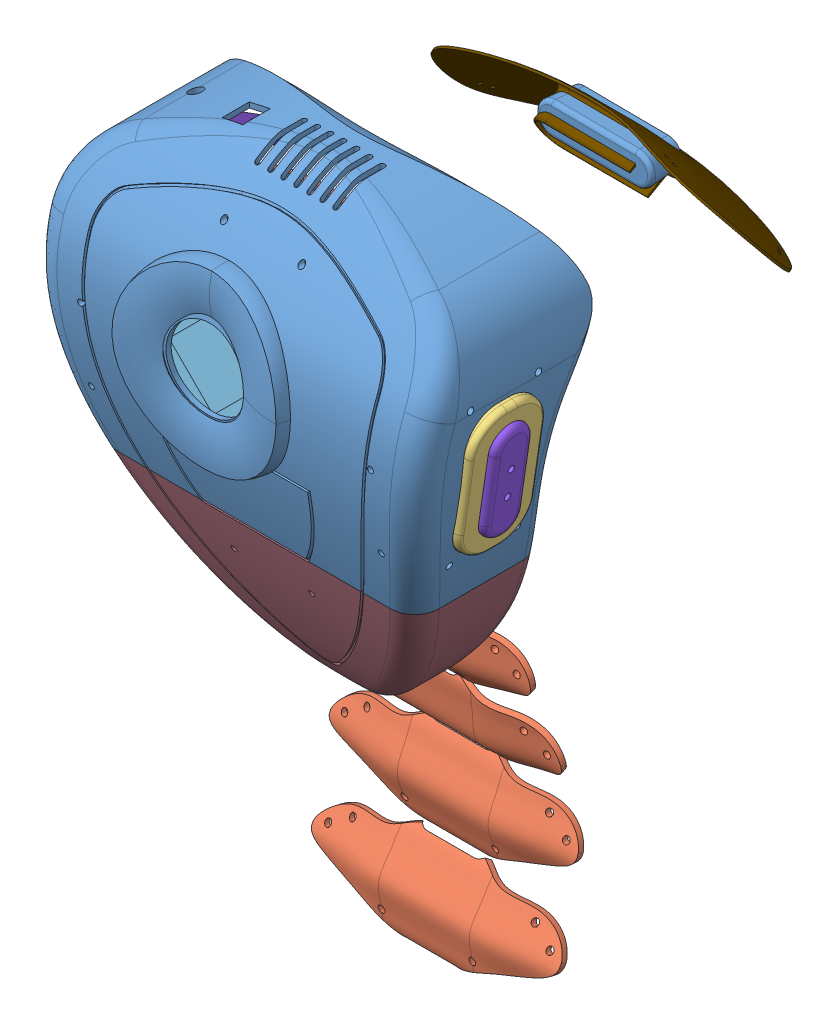
SolidWorks assembly Ensamble Mochila Render, configuration Default. Lengths in mm.
Overall size (331.65 592.36 403.8).
29 component instances, 21 part files, 47 mates.
Components (placement in the parent):
- backpack 2g bottom-1: backpack 2g bottom [Default] at (119.4145 250.7971 218.3899) size (331.65 355.76 156.42)
- Vertebra-1: Vertebra [Default] at (118.8196 71.875 196.4276) x (1 0 0) z (0 -0.948324 -0.317305) size (198 22.76 69.24)
- Part2-1: Part2 [Default] at (-30.5346 255.3553 293.3899) x (0.14708 -0.989125 0) z (0 0 1) size (104.05 10.05 58.05)
- Part2-2: Part2 [Default] at (269.3635 255.3553 293.3899) x (0.147081 0.989124 0) z (0 0 1) size (104.05 10.05 58.05)
- Jetson H-1: Jetson H [Default] at (-25.9313 294.8879 198.9465) x (0.707107 0.707107 0) z (0.707107 -0.707107 0) size (180 45.5 180)
  - Base-1: Base [Default] at (67.0689 90.6709 139.4266) size (180 3 180)
  - Board-1: Board [Default] at (67.0689 104.6709 139.4266) size (170 31.5 170)
  - Separador-1: Separador [Default] at (-7.9311 93.6709 214.4266) x (0.99477 0 -0.102141) z (0.102141 0 0.99477) size (6 11 6)
  - Separador-2: Separador [Default] at (142.0689 93.6709 64.4266) size (6 11 6)
  - Separador-3: Separador [Default] at (142.0689 93.6709 214.4266) size (6 11 6)
  - Separador-4: Separador [Default] at (-7.9311 93.6709 64.4266) size (6 11 6)
- Vertebra-2: Vertebra [Default] at (118.376 8.3161 174.5883) x (1 0 0) z (0 -0.913545 -0.406737) size (198 22.76 69.24)
- Vertebra-3: Vertebra [Default] at (118.6698 -138.0838 164.6524) x (1 0 0) z (0 -0.97237 0.233445) size (198 22.76 69.24)
- Vertebra-4: Vertebra [Default] at (118.6834 -66.4172 153.1876) x (1 0 0) z (0 -0.998135 0.061049) size (198 22.76 69.24)
- Pieza soporte bocina izquierda-1: Pieza soporte bocina izquierda [Default] at (249.7444 259.3959 292.8923) x (0.989124 -0.147081 0) z (0 0 1) size (30.45 130 93.17)
- Seguro bocina izquierda-1: Seguro bocina izquierda [Default] at (260.7409 231.3626 293.3899) x (0 0 -1) z (-0.147081 -0.989124 0) size (30 10.46 80)
- jetson holder ---1: jetson holder -- [Default] at (120.0816 243.7182 283.6173) x (-0.707107 0.707107 0) z (0.707107 0.707107 0) size (66.79 36.44 66.79)
- jetson holder ++-1: jetson holder ++ [Default] at (120.0846 243.7282 283.6173) x (0.707107 -0.707107 0) z (-0.707107 -0.707107 0) size (66.79 46.69 66.79)
- jetson holder -+-1: jetson holder -+ [Default] at (120.0781 243.7248 283.6173) x (0.707107 0.707107 0) z (0.707107 -0.707107 0) size (66.79 69.99 66.79)
- jetson holder +--1: jetson holder +- [Default] at (120.0881 243.7217 283.6173) x (-0.707107 -0.707107 0) z (-0.707107 0.707107 0) size (49.73 64.72 58.31)
- backpack 2g-2: backpack 2g [Default] at (119.4145 250.7971 218.3899) size (250.08 344.21 137.51)
- Pieza soporte bocina derecha-1: Pieza soporte bocina derecha [Default] at (8.867 262.3374 292.8923) x (0.989125 0.14708 0) z (0 0 1) size (17.29 130.75 82.59)
- Seguro bocina der-1: Seguro bocina der [Default] at (-68.831 274.9356 293.3899) x (0 0 1) z (-0.14708 0.989125 0) size (30 10.46 80)
- Union left-1: Union left [Default] at (232.1995 167.8342 278.3854) x (0.008119 -0.003198 -0.999962) z (0.930382 -0.366487 0.008727) size (60 40 6.53)
- Sensores-1: Sensores [Default] at (34.9607 359.3668 269.7709) x (-0.936644 -0.350185 -0.008276) z (0.006782 0.005492 -0.999962) size (110 12.3 30)
- Pecho-1: Pecho [Default] at (116.361 294.6343 51.4593) x (-0.999962 -0.006171 -0.006171) z (0.008727 -0.70708 -0.70708) size (284.4 58.67 170.86)
- Realsense-1: Realsense [Default] at (117.2497 289.9091 71.9103) x (-0.999962 0 -0.008727) z (0.008727 0 -0.999962) size (89.45 24.73 25)
- Broche-1: Broche [Default] at (120.0846 243.7282 283.6173) x (0.965926 -0.258819 0) z (0.258819 0.965926 0) size (250 4 250)
- Galss-1: Galss [Default] at (84.9691 289.9091 46.6277) x (0.999962 0 0.008727) z (-0.008727 0 0.999962) size (82.62 17.62 0.5)
Mates (geometry in assembly coordinates):
- Coincident1: coincident: point of backpack 2g bottom-1; point of Part2-2
- Coincident2: coincident: curve of backpack 2g bottom-1; unknown of Part2-2
- Coincident3: coincident anti-aligned: plane of backpack 2g bottom-1 through (-50.2025 228.7971 264.3899) normal (0 0 1); plane of Part2-2 through (263.4435 283.5325 264.3899) normal (0 0 -1)
- Coincident4: coincident: point of backpack 2g bottom-1; point of Part2-1
- Coincident5: coincident: edge_curve of backpack 2g bottom-1; unknown of Part2-1
- Coincident6: coincident anti-aligned: plane of backpack 2g bottom-1 through (-50.2025 228.7971 264.3899) normal (0 0 1); plane of Part2-1 through (-16.6722 230.1198 264.3899) normal (0 0 -1)
- Concentric1: concentric aligned: cylinder of backpack 2g bottom-1 through (331.3037 303.8839 266.8923) axis (-0.989124 0.147081 0) radius 2.5; cylinder of Pieza soporte bocina izquierda-1 through (272.8178 312.5806 266.8923) axis (-0.989124 0.147081 0) radius 2.5
- Concentric2: concentric aligned: cylinder of backpack 2g bottom-1 through (331.3037 303.8839 318.8923) axis (-0.989124 0.147081 0) radius 2.5; cylinder of Pieza soporte bocina izquierda-1 through (272.8178 312.5806 318.8923) axis (-0.989124 0.147081 0) radius 2.5
- Coincident7: coincident anti-aligned: plane of Part2-2 through (255.5011 230.1198 289.3899) normal (-0.989124 0.147081 0); plane of Pieza soporte bocina izquierda-1 through (255.5011 230.1198 289.3899) normal (0.989124 -0.147081 0)
- Concentric3: concentric aligned: cylinder of Pieza soporte bocina izquierda-1 through (245.6146 268.9967 293.3899) axis (0.989124 -0.147081 0) radius 2.5; cylinder of Seguro bocina izquierda-1 through (265.4344 266.0495 293.3899) axis (0.989124 -0.147081 0) radius 2.5
- Concentric4: concentric aligned: cylinder of Pieza soporte bocina izquierda-1 through (242.673 249.2142 293.3899) axis (0.989124 -0.147081 0) radius 2.5; cylinder of Seguro bocina izquierda-1 through (262.4928 246.267 293.3899) axis (0.989124 -0.147081 0) radius 2.5
- Coincident8: coincident anti-aligned: plane of Pieza soporte bocina izquierda-1 through (264.5813 257.1896 292.8923) normal (0.989124 -0.147081 0); plane of Seguro bocina izquierda-1 through (260.7409 231.3626 293.3899) normal (-0.989124 0.147081 0)
- Concentric5: concentric anti-aligned: cylinder of Jetson H-1/Base-1 through (110.0816 132.6368 292.6173) axis (0 0 -1) radius 2.5; cylinder of jetson holder ---1 through (110.0816 132.6368 283.6163) axis (0 0 1) radius 2.5
- Parallel1: parallel anti-aligned: cylinder of Jetson H-1/Base-1 through (130.0816 132.6368 292.6173) axis (0 0 -1) radius 2.5; cylinder of jetson holder ---1 through (130.0816 132.6368 283.6163) axis (0 0 1) radius 2.5
- Coincident9: coincident anti-aligned: plane of Jetson H-1/Base-1 through (120.0831 243.7232 289.6173) normal (0 0 -1); plane of jetson holder ---1 through (120.0816 243.7182 289.6173) normal (0 0 1)
- Coincident10: coincident aligned: circle of Jetson H-1/Base-1; cylinder of jetson holder ++-1 through (130.0846 354.8097 283.6163) axis (0 0 1) radius 2.5
- Parallel2: parallel anti-aligned: cylinder of Jetson H-1/Base-1 through (110.0846 354.8097 292.6173) axis (0 0 -1) radius 2.5; cylinder of jetson holder ++-1 through (110.0846 354.8097 283.6163) axis (0 0 1) radius 2.5
- Coincident11: coincident anti-aligned: plane of Jetson H-1/Base-1 through (120.0831 243.7232 289.6173) normal (0 0 -1); plane of jetson holder ++-1 through (120.0846 243.7282 289.6173) normal (0 0 1)
- Concentric8: concentric anti-aligned: cylinder of Jetson H-1/Base-1 through (8.9966 253.7248 292.6173) axis (0 0 -1) radius 2.5; cylinder of jetson holder -+-1 through (8.9966 253.7248 283.6163) axis (0 0 1) radius 2.5
- Parallel3: parallel anti-aligned: cylinder of Jetson H-1/Base-1 through (8.9966 233.7248 292.6173) axis (0 0 -1) radius 2.5; cylinder of jetson holder -+-1 through (8.9966 233.7248 283.6163) axis (0 0 1) radius 2.5
- Coincident12: coincident anti-aligned: plane of Jetson H-1/Base-1 through (120.0831 243.7232 289.6173) normal (0 0 -1); plane of jetson holder -+-1 through (120.0781 243.7248 289.6173) normal (0 0 1)
- Concentric10: concentric anti-aligned: cylinder of Jetson H-1/Base-1 through (231.1696 233.7217 292.6173) axis (0 0 -1) radius 2.5; cylinder of jetson holder +--1 through (231.1696 233.7217 283.6163) axis (0 0 1) radius 2.5
- Parallel4: parallel anti-aligned: cylinder of Jetson H-1/Base-1 through (231.1696 253.7217 292.6173) axis (0 0 -1) radius 2.5; cylinder of jetson holder +--1 through (231.1696 253.7217 283.6163) axis (0 0 1) radius 2.5
- Coincident13: coincident anti-aligned: plane of Jetson H-1/Base-1 through (120.0831 243.7232 289.6173) normal (0 0 -1); plane of jetson holder +--1 through (120.0881 243.7217 289.6173) normal (0 0 1)
- Parallel5: parallel anti-aligned: cylinder of Jetson H-1/Base-1 through (110.0846 354.8097 292.6173) axis (0 0 -1) radius 2.5; cylinder of jetson holder ++-1 through (110.0846 354.8097 283.6163) axis (0 0 1) radius 2.5
- Parallel6: parallel anti-aligned: cylinder of Jetson H-1/Base-1 through (110.0846 354.8097 292.6173) axis (0 0 -1) radius 2.5; cylinder of jetson holder ++-1 through (110.0846 354.8097 283.6163) axis (0 0 1) radius 2.5
- Concentric15: concentric anti-aligned: cylinder of Jetson H-1/Base-1 through (110.0846 354.8097 292.6173) axis (0 0 -1) radius 2.5; cylinder of jetson holder ++-1 through (110.0846 354.8097 283.6163) axis (0 0 1) radius 2.5
- Concentric16: concentric anti-aligned: cylinder of Jetson H-1/Base-1 through (8.9966 233.7248 292.6173) axis (0 0 -1) radius 2.5; cylinder of jetson holder -+-1 through (8.9966 233.7248 283.6163) axis (0 0 1) radius 2.5
- Concentric17: concentric anti-aligned: cylinder of Jetson H-1/Base-1 through (130.0816 132.6368 292.6173) axis (0 0 -1) radius 2.5; cylinder of jetson holder ---1 through (130.0816 132.6368 283.6163) axis (0 0 1) radius 2.5
- Concentric18: concentric anti-aligned: cylinder of Jetson H-1/Base-1 through (231.1696 253.7217 292.6173) axis (0 0 -1) radius 2.5; cylinder of jetson holder +--1 through (231.1696 253.7217 283.6163) axis (0 0 1) radius 2.5
- Concentric19: concentric aligned: cylinder of backpack 2g bottom-1 through (90.3204 354.8097 376.5741) axis (0 0 -1) radius 2.25; cylinder of jetson holder ++-1 through (90.3204 354.8097 333.6173) axis (0 0 -1) radius 2.5
- Concentric20: concentric aligned: cylinder of backpack 2g bottom-1 through (149.8488 354.8097 376.5741) axis (0 0 -1) radius 2.25; cylinder of jetson holder ++-1 through (149.8488 354.8097 333.6173) axis (0 0 -1) radius 2.5
- Coincident15: coincident: point of backpack 2g bottom-1; point of backpack 2g-2
- Coincident16: coincident: point of backpack 2g bottom-1; point of backpack 2g-2
- Coincident17: coincident anti-aligned: plane of Part2-1 through (-24.6145 283.5325 289.3899) normal (0.989125 0.14708 0); plane of Pieza soporte bocina derecha-1 through (-16.6722 230.1198 289.3899) normal (-0.989125 -0.14708 0)
- Coincident18: coincident: point of Part2-1; point of Pieza soporte bocina derecha-1
- Coincident19: coincident: point of Part2-1; point of Pieza soporte bocina derecha-1
- Concentric21: concentric aligned: cylinder of Pieza soporte bocina derecha-1 through (-6.7857 268.9967 293.3899) axis (-0.989125 -0.14708 0) radius 2.5; cylinder of Seguro bocina der-1 through (-26.6055 266.0495 293.3899) axis (-0.989125 -0.14708 0) radius 2.5
- Concentric22: concentric aligned: cylinder of Pieza soporte bocina derecha-1 through (-3.8441 249.2142 293.3899) axis (-0.989125 -0.14708 0) radius 2.5; cylinder of Seguro bocina der-1 through (-23.6639 246.267 293.3899) axis (-0.989125 -0.14708 0) radius 2.5
- Coincident20: coincident anti-aligned: plane of Pieza soporte bocina derecha-1 through (-25.7524 257.1896 292.8923) normal (-0.989125 -0.14708 0); plane of Seguro bocina der-1 through (-29.266 280.8188 293.3899) normal (0.989125 0.14708 0)
- Coincident21: coincident: point of backpack 2g bottom-1; point of backpack 2g-2
- Coincident22: coincident anti-aligned: plane of jetson holder ++-1 through (120.0846 243.7282 283.6173) normal (0 0 -1); plane of Broche-1 through (120.0846 243.7282 283.6173) normal (0 0 1)
- Concentric23: concentric anti-aligned: cylinder of jetson holder ++-1 through (149.8488 354.8097 333.6173) axis (0 0 -1) radius 2.5; cylinder of Broche-1 through (149.8488 354.8097 279.6173) axis (0 0 1) radius 2.5
- Concentric24: concentric anti-aligned: cylinder of jetson holder ++-1 through (90.3204 354.8097 333.6173) axis (0 0 -1) radius 2.5; cylinder of Broche-1 through (90.3204 354.8097 279.6173) axis (0 0 1) radius 2.5
- Coincident23: coincident anti-aligned: plane of Realsense-1 through (117.4635 289.9091 47.4113) normal (0.008727 0 -0.999962); plane of Galss-1 through (84.9648 289.9091 47.1276) normal (-0.008727 0 0.999962)
- Concentric26: concentric anti-aligned: circle of Realsense-1; circle of Galss-1
- Concentric27: concentric aligned: circle of Realsense-1; cylinder of Galss-1 through (149.9623 289.9091 47.6949) axis (0.008727 0 -0.999962) radius 8.81
